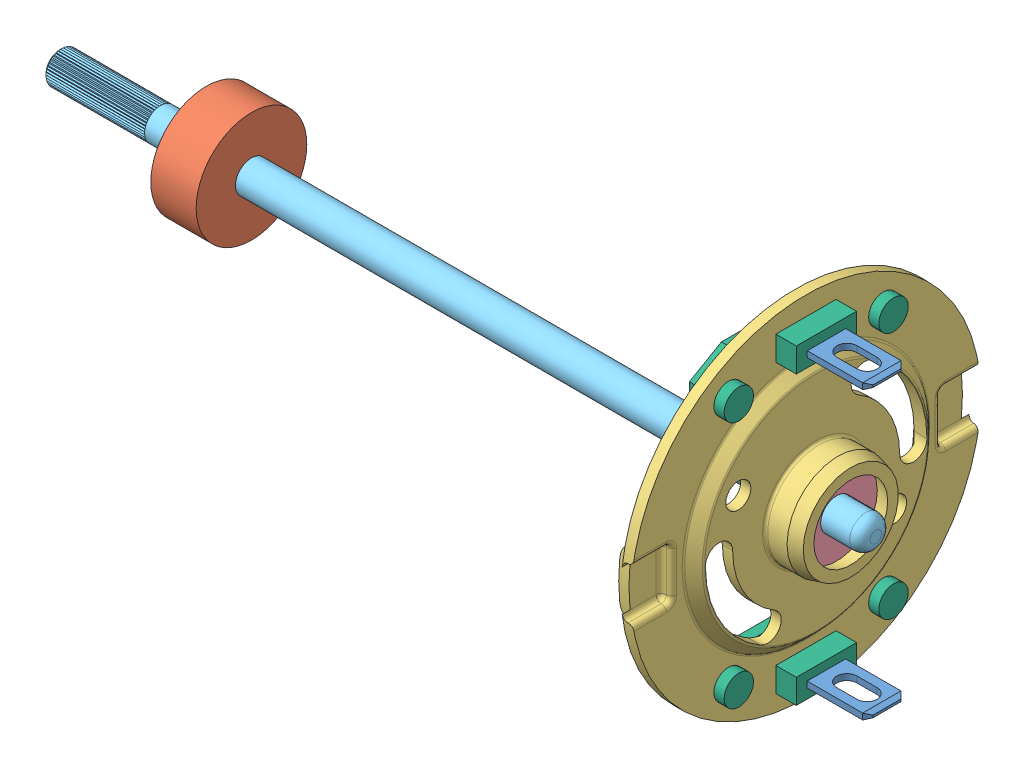
SolidWorks assembly PG 9015, configuration Default. Lengths in mm.
Overall size (82.02 34.65 34.46).
8 component instances, 6 part files, 0 mates.
Components (placement in the parent):
- AM-0912 terminal-1: AM-0912 terminal [Default] at (29.27 -13.055 -1.5854) size (10.06 0.6 3.8)
- AM-0912 output bushing-1: AM-0912 output bushing [Default] at (-28.166 1.123 -1.5904) size (4.5 10.97 10.97)
- AM-0912 end cap-1: AM-0912 end cap [Default] at (24.952 1.123 -1.5904) size (6.48 34.65 34.46)
- AM-0912 cap bushing-1: AM-0912 cap bushing [Default] at (31.302 1.123 -1.5904) size (3.04 8.08 8.08)
- AM-0912 shaft-1: AM-0912 shaft [Default] at (-32.682 1.123 -1.5904) x (1 0 0) z (0 0.970706 0.240271) size (80.92 3.29 3.26)
- AM-0912 terminal housing-1: AM-0912 terminal housing [Default] at (30.286 -13.101 -1.5904) x (-1 0 0) z (0 0 1) size (4.06 4.83 19.05)
- AM-0912 terminal housing-2: AM-0912 terminal housing [Default] at (30.286 15.347 -1.5904) x (-1 0 0) z (0 0 -1) size (4.06 4.83 19.05)
- AM-0912 terminal-2: AM-0912 terminal [Default] at (29.27 15.301 -1.5954) size (10.06 0.6 3.8)
